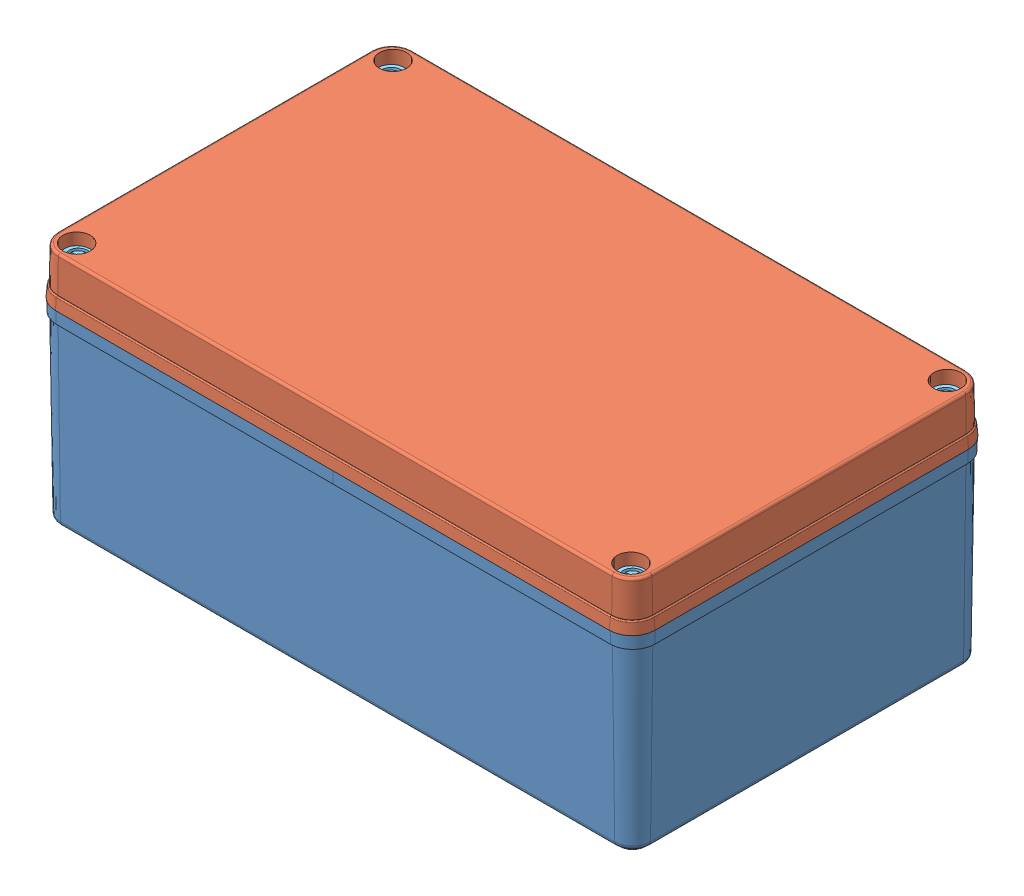
SolidWorks assembly LeMotech IP67 Junction Box, 250 mm x 150 mm x 100 mm, configuration Default. Lengths in mm.
Overall size (252 101 151).
9 component instances, 5 part files, 13 mates.
Components (placement in the parent):
- Enclosure, LeMotech IP67 Junction Box, 250 mm x 150 mm x 100 mm-2: Enclosure, LeMotech IP67 Junction Box, 250 mm x 150 mm x 100 mm [Default] at origin size (251.8 83 150.4)
- Cover, LeMotech IP67 Junction Box, 250 mm x 150 mm x 100 mm-1: Cover, LeMotech IP67 Junction Box, 250 mm x 150 mm x 100 mm [Default] at (0 80 0) size (252 20 151)
- O-ring, LeMotech IP67 Junction Box, 250 mm x 150 mm x 100 mm-1: O-ring, LeMotech IP67 Junction Box, 250 mm x 150 mm x 100 mm [Default] at (0 81.2 0) size (249.6 3 148.6)
- M4 Insert, LeMotech IP67 Junction Box, 250 mm x 150 mm x 100 mm-1: M4 Insert, LeMotech IP67 Junction Box, 250 mm x 150 mm x 100 mm [default] at (-109 3.1 0) x (1 0 0) z (0 -1 0) size (5.5 5.5 7.76)
- M4 Insert, LeMotech IP67 Junction Box, 250 mm x 150 mm x 100 mm-2: M4 Insert, LeMotech IP67 Junction Box, 250 mm x 150 mm x 100 mm [default] at (109 3.1 0) x (-1 0 0) z (0 -1 0) size (5.5 5.5 7.76)
- Screw, LeMotech IP67 Junction Box, 250 mm x 150 mm x 100 mm-1: Screw, LeMotech IP67 Junction Box, 250 mm x 150 mm x 100 mm [Default] at (-116.5 95 65.8) x (-1 0 0) z (0 0 -1) size (11 37 11)
- Screw, LeMotech IP67 Junction Box, 250 mm x 150 mm x 100 mm-2: Screw, LeMotech IP67 Junction Box, 250 mm x 150 mm x 100 mm [Default] at (116.5 95 65.8) x (-1 0 0) z (0 0 -1) size (11 37 11)
- Screw, LeMotech IP67 Junction Box, 250 mm x 150 mm x 100 mm-3: Screw, LeMotech IP67 Junction Box, 250 mm x 150 mm x 100 mm [Default] at (-116.5 95 -65.8) size (11 37 11)
- Screw, LeMotech IP67 Junction Box, 250 mm x 150 mm x 100 mm-4: Screw, LeMotech IP67 Junction Box, 250 mm x 150 mm x 100 mm [Default] at (116.5 95 -65.8) size (11 37 11)
Mates (geometry in assembly coordinates):
- Coincident2: coincident: plane of assembly; plane of assembly; plane of Cover, LeMotech IP67 Junction Box, 250 mm x 150 mm x 100 mm-1 through (0 80 0) normal (1 0 0); plane of O-ring, LeMotech IP67 Junction Box, 250 mm x 150 mm x 100 mm-1 through (0 81.2 0) normal (1 0 0)
- Coincident7: coincident: plane of assembly; plane of assembly; plane of Cover, LeMotech IP67 Junction Box, 250 mm x 150 mm x 100 mm-1 through (0 80 0) normal (0 0 1); plane of O-ring, LeMotech IP67 Junction Box, 250 mm x 150 mm x 100 mm-1 through (0 81.2 0) normal (0 0 1)
- Tangent1: tangent: plane of assembly; plane of Cover, LeMotech IP67 Junction Box, 250 mm x 150 mm x 100 mm-1 through (-116.5 82.7 66.5) normal (0 -1 0); face of O-ring, LeMotech IP67 Junction Box, 250 mm x 150 mm x 100 mm-1
- Coincident14: coordinate: point of assembly; point of Enclosure, LeMotech IP67 Junction Box, 250 mm x 150 mm x 100 mm-2; point of assembly
- Coincident15: coincident: plane of assembly through (0 0 0) normal (1 0 0); plane of Cover, LeMotech IP67 Junction Box, 250 mm x 150 mm x 100 mm-1 through (0 80 0) normal (1 0 0); plane of assembly
- Coincident16: coincident: plane of assembly through (0 0 0) normal (0 0 1); plane of Cover, LeMotech IP67 Junction Box, 250 mm x 150 mm x 100 mm-1 through (0 80 0) normal (0 0 1); plane of assembly
- Coincident17: coincident: plane of assembly; plane of assembly; plane of Enclosure, LeMotech IP67 Junction Box, 250 mm x 150 mm x 100 mm-2 through (116.5 80 65.8) normal (0 1 0); plane of Cover, LeMotech IP67 Junction Box, 250 mm x 150 mm x 100 mm-1 through (-116.4 80 65.9) normal (0 -1 0)
- Concentric1: concentric: cylinder of assembly; line of assembly; cylinder of Enclosure, LeMotech IP67 Junction Box, 250 mm x 150 mm x 100 mm-2 through (-109 -5.0368 0) axis (0 1 0) radius 2.7; axis of M4 Insert, LeMotech IP67 Junction Box, 250 mm x 150 mm x 100 mm-1 through (4.8858 -109 8.4058) axis (0 0 -1)
- Coincident18: coincident: plane of assembly; plane of assembly; plane of Enclosure, LeMotech IP67 Junction Box, 250 mm x 150 mm x 100 mm-2 through (-109 10.6 0) normal (0 1 0); plane of M4 Insert, LeMotech IP67 Junction Box, 250 mm x 150 mm x 100 mm-1 through (-109 10.6 0) normal (0 1 0)
- Parallel1: parallel: plane of assembly through (0 0 0) normal (1 0 0); plane of M4 Insert, LeMotech IP67 Junction Box, 250 mm x 150 mm x 100 mm-1 through (-109 3.1 0) normal (1 0 0); plane of assembly
- Concentric2: concentric: cylinder of assembly; cylinder of assembly; cylinder of Enclosure, LeMotech IP67 Junction Box, 250 mm x 150 mm x 100 mm-2 through (-116.5 -10.835 65.8) axis (0 1 0) radius 4.75; cylinder of Screw, LeMotech IP67 Junction Box, 250 mm x 150 mm x 100 mm-1 through (-116.5 58 65.8) axis (0 -1 0) radius 3.5
- Coincident19: coincident: plane of assembly; plane of assembly; plane of Cover, LeMotech IP67 Junction Box, 250 mm x 150 mm x 100 mm-1 through (-116.4 84 65.9) normal (0 1 0); plane of Screw, LeMotech IP67 Junction Box, 250 mm x 150 mm x 100 mm-1 through (-122 84 65.8) normal (0 -1 0)
- Parallel2: parallel: plane of assembly through (0 0 0) normal (1 0 0); plane of Screw, LeMotech IP67 Junction Box, 250 mm x 150 mm x 100 mm-1 through (-116.5 95 65.8) normal (-1 0 0); plane of assembly
